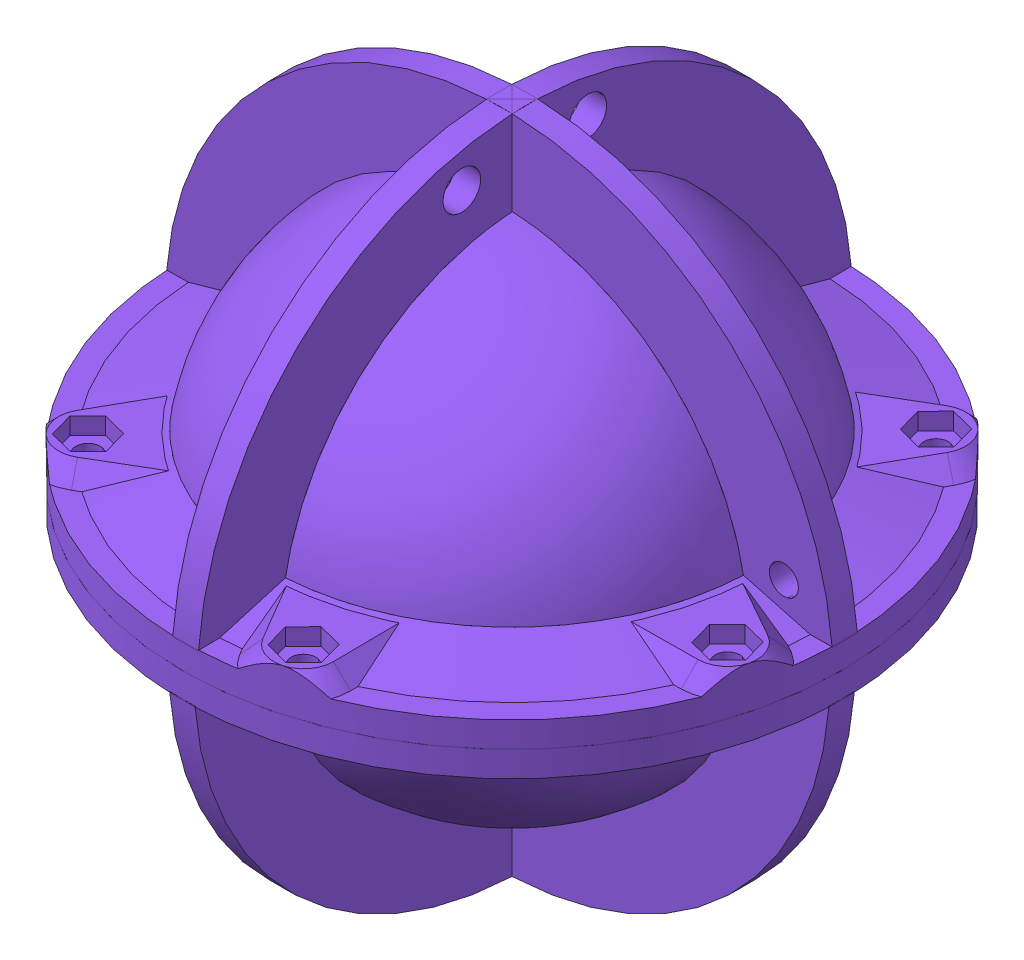
SolidWorks assembly Drifter2_Assem1, configuration Default. Lengths in mm.
Overall size (78.43 77.92 78.43).
11 component instances, 10 part files, 37 mates.
Components (placement in the parent):
- Sparkfun_NEO-M8P-1: Sparkfun_NEO-M8P [Default] at (0 -4.15 0) x (-1 0 0) z (0 0 -1) size (33 4.73 41.24)
- TAOGLAS_AGPP25F-1: TAOGLAS_AGPP25F [Default] at (0 -16.4 0) x (0 0 1) z (1 0 0) size (25.1 7.4 25.1)
- Teensy_3-2-1: Teensy_3-2 [Default] at (0 -7.15 0) x (0 0 1) z (1 0 0) size (35.56 4.07 17.78)
- Battery_AllSizes_configurations-5: Battery_AllSizes_configurations [500mAH] at (0 18.5 0) size (31 9 20)
- internalmounts-1: internalmounts [Default] at (0 -4.15 0) x (1 0 0) z (0 0 -1) size (12.5 3 41.24)
- Pimoroni_ICM20948-1: Pimoroni_ICM20948 [Default] at (0 -14 0) x (0 0 -1) z (1 0 0) size (19 2.7 19)
- GPSmount-2: GPSmount [Default] at (0 -19 0) x (0 0 1) z (1 0 0) size (41.56 19.45 33.94)
- housing2_rev2-1: housing2_rev2 [2-140] at origin size (77.69 38.96 77.69)
- housing2_rev2-3: housing2_rev2 [2-140_UP] x (-0.00956 0 -0.999954) z (-0.999954 0 0.00956) size (77.69 40.96 77.69)
- Sparkfun_RFM69HCW_transceiver-1: Sparkfun_RFM69HCW_transceiver [Default] at (-14.53 -12.014 0.1156) x (0 1 0) z (0 0 1) size (16 1.57 16)
- 2418T159_Oil-Resistant Soft Buna-N O-Rings-1: 2418T159_Oil-Resistant Soft Buna-N O-Rings [2418T159] at (0 -0.6477 0) x (0.964398 0 -0.264454) z (0 -1 0) size (62.05 62.05 2.62)
Mates (geometry in assembly coordinates):
- Coincident2: coincident: point of Sparkfun_NEO-M8P-1
- Coincident3: coincident: unknown of TAOGLAS_AGPP25F-1
- Coincident4: coincident: unknown of Teensy_3-2-1
- Parallel1: parallel anti-aligned: plane of Teensy_3-2-1 through (-8.89 -8.72 -17.78) normal (0 0 -1)
- Parallel3: parallel aligned: plane of TAOGLAS_AGPP25F-1 through (12.55 -17.23 -12.55) normal (1 0 0)
- Parallel7: parallel aligned: plane of Teensy_3-2-1 through (8.89 -8.72 -17.78) normal (1 0 0)
- Parallel11: parallel aligned: plane of TAOGLAS_AGPP25F-1 through (0 -16.4 0) normal (0 0 1)
- Coincident26: coincident aligned: plane of Battery_AllSizes_configurations-5 through (0 18.5 0) normal (1 0 0)
- Coincident42: coincident: unknown of internalmounts-1
- Parallel12: parallel anti-aligned: plane of internalmounts-1 through (0 -4.15 0) normal (0 -1 0)
- Coincident44: coincident aligned: plane of internalmounts-1 through (0 -4.15 0) normal (1 0 0)
- Coincident46: coincident: unknown of Pimoroni_ICM20948-1
- Coincident47: coincident anti-aligned: plane of TAOGLAS_AGPP25F-1 through (0 -14 0) normal (0 1 0); plane of Pimoroni_ICM20948-1 through (0 -14 0) normal (0 -1 0)
- Coincident52: coincident: unknown of GPSmount-2
- Parallel13: parallel anti-aligned: plane of GPSmount-2 through (0 -19 0) normal (0 -1 0)
- Coincident54: coincident aligned: plane of GPSmount-2 through (0 -19 0) normal (1 0 0)
- Coincident55: coincident anti-aligned: plane of TAOGLAS_AGPP25F-1 through (0 -16.4 0) normal (0 1 0); plane of GPSmount-2 through (0 -16.4 12.5) normal (0 -1 0)
- Coincident58: coincident anti-aligned: plane of Pimoroni_ICM20948-1 through (0 -14 0) normal (0 0 -1)
- Parallel16: parallel aligned: plane of Sparkfun_NEO-M8P-1 through (0 -4.15 0) normal (0 1 0)
- Coincident65: coincident anti-aligned: plane of Sparkfun_NEO-M8P-1 through (0 -4.15 0) normal (-1 0 0)
- Coincident66: coincident anti-aligned: plane of Sparkfun_NEO-M8P-1 through (0 -4.15 0) normal (0 -1 0); plane of internalmounts-1 through (0 -4.15 0) normal (0 1 0)
- Coincident67: coincident anti-aligned: plane of Teensy_3-2-1 through (0 -7.15 0) normal (0 1 0); plane of internalmounts-1 through (0 -7.15 0) normal (0 -1 0)
- Coincident68: coincident anti-aligned: plane of Sparkfun_NEO-M8P-1 through (0 -4.15 0) normal (0 -1 0); plane of GPSmount-2 through (0 -4.15 0) normal (0 1 0)
- Coincident81: coincident: unknown of housing2_rev2-1
- Parallel18: parallel aligned: plane of housing2_rev2-1 through (0 0 0) normal (0 1 0)
- Coincident82: coincident aligned: plane of housing2_rev2-1 through (0 0 0) normal (0 0 1)
- Concentric3: concentric: sphere of GPSmount-2; sphere of housing2_rev2-1
- Parallel19: parallel anti-aligned: plane of Sparkfun_RFM69HCW_transceiver-1 through (-14.53 -12.014 0.1156) normal (-1 0 0)
- Coincident101: coincident: unknown of housing2_rev2-3
- Parallel20: parallel anti-aligned: plane of housing2_rev2-3 through (0 0 0) normal (0 -1 0)
- Coincident99: coincident anti-aligned: unknown of housing2_rev2-3
- Coincident100: coincident: unknown of housing2_rev2-3
- Coincident103: coordinate: unknown of housing2_rev2-1
- Coincident107: coincident: unknown of 2418T159_Oil-Resistant Soft Buna-N O-Rings-1
- Tangent1: tangent anti-aligned: plane of housing2_rev2-1 through (0 -1.9558 0) normal (0 1 0); torus of 2418T159_Oil-Resistant Soft Buna-N O-Rings-1
- Coincident109: coincident: unknown of Battery_AllSizes_configurations-5
- Distance1: distance = 16 mm aligned: plane of housing2_rev2-3 through (0 -2 0) normal (0 -1 0); plane of Battery_AllSizes_configurations-5 through (0 14 0) normal (0 -1 0)
